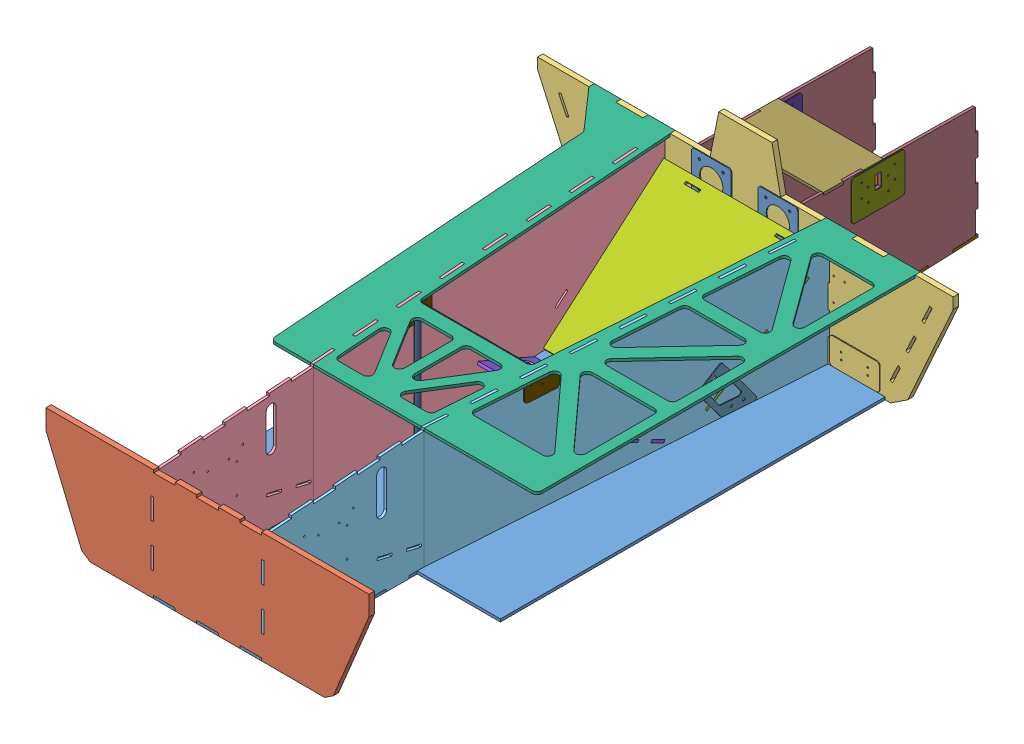
SolidWorks assembly Interior Frame, configuration Default. Lengths in mm.
Overall size (1586.02 634.29 2739.24).
38 component instances, 24 part files, 124 mates.
Components (placement in the parent):
- Floor Panel-1: Floor Panel [Default] at (835.5965 1316.5356 1074.9175) x (1 0 0) z (0 -1 0) size (1066.76 2072.64 10.16)
- Front Bulkhead-1: Front Bulkhead [Default] at (162.873 1776.2756 3127.2375) size (1232.36 425.45 20.32)
- Rearward Bulkhead-1: Rearward Bulkhead [Default] at (876.0943 1625.7899 1074.9175) size (1586.02 634.29 20.32)
- Part11-1: Part11 [Default] at (835.5965 1306.3756 1074.9175) x (1 0 0) z (0 -1 0) size (111.78 2072.64 469.9)
- MirrorPart11-2: MirrorPart11 [Default] at (835.5965 1306.3756 1074.9175) x (-1 0 0) z (0 1 0) size (111.78 2072.64 469.9)
- Part12-1: Part12 [Default] at (835.5965 1766.1156 1074.9175) x (-1 0 0) z (0 1 0) size (1244.67 1463.04 10.16)
- Part13-1: Part13 [Default] at origin
- Part14-1: Part14 [Default] at (835.5965 0 0) x (0 0 -1) z (1 0 0) size (499.77 372.73 622.87)
- Part15-1: Part15 [Default] at (835.5965 0 0) x (0 0 -1) z (1 0 0) size (234.38 107.63 550.98)
- Battery Tray-1: Battery Tray [Default] at (634.9365 1306.3843 1074.4968) x (1 0 0) z (0 -0.041404 0.999142) size (401.32 10.16 666.75)
- Part5^Interior Frame-1: Part5^Interior Frame [Default] at (0 0 2118.8575) size (473.12 449.58 19.05) (virtual)
- Part6^Interior Frame-1: Part6^Interior Frame [Default] at (0 0 2118.8575) size (50.8 31.75 1.65) (virtual)
- Part1^Interior Frame-1: Part1^Interior Frame [Default] at (1026.0965 1782.5715 1439.818) x (0 -0.013523 -0.999909) z (0 0.999909 -0.013523) size (228.6 401.32 10.16) (virtual)
- Shock Side Holder-1: Shock Side Holder [Default] at (634.9365 1306.3881 1094.817) x (0 0 -1) z (1 0 0) size (686.5 467.3 10.16)
- Shock Side Holder-2: Shock Side Holder [Default] at (1026.0965 1306.3881 1094.817) x (0 0 -1) z (1 0 0) size (686.5 467.3 10.16)
- Waist Seatbelt Bracket Outside-1: Waist Seatbelt Bracket Outside [Default] at (519.6209 1306.3756 1096.8642) x (0 -1 0) z (-0.997597 0 0.06929) size (178.19 207.85 3.17)
- Waist Seatbelt Bracket Outside-2: Waist Seatbelt Bracket Outside [Default] at (1154.7396 1306.3756 1097.0842) x (0 -1 0) z (-0.997597 0 -0.06929) size (178.19 207.85 3.17)
- Waist Seatbelt Bracket Inside-1: Waist Seatbelt Bracket Inside [Default] at (529.7386 1306.3756 1096.1614) x (0 1 0) z (0.997597 0 -0.06929) size (100.47 160.16 3.17)
- RearSuspensionBracketOutside-1: RearSuspensionBracketOutside [Default] at (634.9365 1306.3881 1094.817) x (0 0 1) z (-1 0 0) size (203.2 152.4 3.17)
- RearSuspensionBracketInside-1: RearSuspensionBracketInside [Default] at (645.0965 1306.3881 1094.817) x (0 0 -1) z (1 0 0) size (203.2 127 3.17)
- RearSuspensionBracketInside-2: RearSuspensionBracketInside [Default] at (1026.0965 1306.3881 488.5782) x (0 0 1) z (-1 0 0) size (203.2 127 3.17)
- RearSuspensionBracketOutside-2: RearSuspensionBracketOutside [Default] at (1039.4315 1306.3881 1094.817) x (0 0 1) z (-1 0 0) size (203.2 152.4 3.17)
- SteeringMountBracket-1: SteeringMountBracket [Default] at (519.6209 1306.3756 1096.8642) x (0 -1 0) z (-0.997597 0 0.06929) size (76.2 127 3.17)
- SteeringMountBracket-2: SteeringMountBracket [Default] at (671.7075 1306.3756 3140.1481) x (0 -1 0) z (0.997597 0 -0.06929) size (76.2 127 3.17)
- SteeringMountBracket-3: SteeringMountBracket [Default] at (1141.4545 1306.3756 1096.1614) x (0 -1 0) z (-0.997597 0 -0.06929) size (76.2 127 3.17)
- SteeringMountBracket-4: SteeringMountBracket [Default] at (1009.6032 1306.3756 3140.8508) x (0 -1 0) z (0.997597 0 0.06929) size (76.2 127 3.17)
- RollBarBackingPlate-1: RollBarBackingPlate [Default] at (876.0943 1625.7899 1095.2375) size (152.4 152.4 3.17)
- RollBarBackingPlate-2: RollBarBackingPlate [Default] at (795.0988 1625.7899 1098.4125) x (-1 0 0) z (0 0 -1) size (152.4 152.4 3.17)
- Array Support Backing Plate-1: Array Support Backing Plate [Default] at (876.0943 1625.7899 1095.2375) size (127 63.5 3.17)
- Rear Suspension Lower Backing Plate-1: Rear Suspension Lower Backing Plate [Default] at (876.0943 1625.7899 1095.2375) size (190.5 101.6 3.17)
- Rear Suspension Lower Backing Plate-2: Rear Suspension Lower Backing Plate [Default] at (37.6403 1625.7899 1095.2375) size (190.5 101.6 3.17)
- Part2^Interior Frame-1: Part2^Interior Frame [Default] at (876.0943 1625.7899 1074.9175) x (-1 0 0) z (0 0 -1) size (292.1 149.22 2.54) (virtual)
- Part2^Interior Frame-2: Part2^Interior Frame [Default] at (876.0943 1625.7899 1097.7775) x (-1 0 0) z (0 0 -1) size (292.1 149.22 2.54) (virtual)
- Part3^Interior Frame-1: Part3^Interior Frame [Default] at (835.5965 453.9768 -212.3723) x (0 -0.423732 -0.905788) z (0 0.905788 -0.423732) size (101.6 38.1 3.17) (virtual)
- Part3^Interior Frame-2: Part3^Interior Frame [Default] at (835.5965 441.8981 -206.7219) x (0 -0.423732 -0.905788) z (0 0.905788 -0.423732) size (101.6 38.1 3.17) (virtual)
- Part3^Interior Frame-3: Part3^Interior Frame [Default] at (1279.1452 453.9768 -212.3723) x (0 -0.423732 -0.905788) z (0 0.905788 -0.423732) size (101.6 38.1 3.17) (virtual)
- Part3^Interior Frame-4: Part3^Interior Frame [Default] at (1279.1452 441.8981 -206.7219) x (0 -0.423732 -0.905788) z (0 0.905788 -0.423732) size (101.6 38.1 3.17) (virtual)
- Waist Seatbelt Bracket Inside-2: Waist Seatbelt Bracket Inside [Default] at (1138.2871 1306.3756 1095.9414) x (0 1 0) z (0.997597 0 0.06929) size (100.47 160.16 3.17)
Mates (geometry in assembly coordinates):
- Coincident5: coincident: point of Floor Panel-1; plane of Rearward Bulkhead-1 through (835.5965 1625.7899 1074.9175) normal (1 0 0)
- Coincident6: coincident aligned: plane of Floor Panel-1 through (835.5965 1306.3756 1074.9175) normal (0 -1 0); plane of Rearward Bulkhead-1 through (876.0943 1306.3756 1095.2375) normal (0 -1 0)
- Coincident7: coincident aligned: plane of Floor Panel-1 through (835.5965 1306.3756 1074.9175) normal (0 0 -1); plane of Rearward Bulkhead-1 through (876.0943 1625.7899 1074.9175) normal (0 0 -1)
- InPlace1: in place: plane of Floor Panel-1 through (835.5965 1306.3756 1074.9175) normal (0 -1 0); plane of ? through (0 1306.3756 0) normal (0 -1 0); moOrthogonalPlaneRef_w of Floor Panel-1 through (835.5965 1306.3756 1074.9175) normal (0 -1 0); plane of ? through (0 1306.3756 0) normal (0 0 -1); plane of Floor Panel-1 through (835.5965 1306.3756 1074.9175) normal (0 -1 0); plane of ? through (0 1306.3756 0) normal (-1 0 0); plane of Floor Panel-1 through (835.5965 1306.3756 1074.9175) normal (0 -1 0); unknown of Part11-1
- Coincident8: coincident aligned: plane of Floor Panel-1; plane of Part11-1
- Coincident9: coincident aligned: moOrthogonalPlaneRef_w of Floor Panel-1 through (835.5965 1306.3756 1074.9175) normal (0 0 1); plane of Part11-1 through (835.5965 1306.3756 1074.9175) normal (0 0 1)
- Coincident10: coincident anti-aligned: moOrthogonalPlaneRef_w of Floor Panel-1 through (835.5965 1306.3756 1074.9175) normal (-1 0 0); plane of Part11-1 through (835.5965 1306.3756 1074.9175) normal (1 0 0)
- InPlace2: in place: plane of Part11-1 through (554.4334 1766.1156 1089.5649) normal (0 1 0); plane of ? through (0 1766.1156 0) normal (0 1 0); plane of Part11-1 through (554.4334 1766.1156 1089.5649) normal (0 1 0); plane of ? through (0 1766.1156 0) normal (0 0 -1); plane of Part11-1 through (554.4334 1766.1156 1089.5649) normal (0 1 0); plane of ? through (0 1766.1156 0) normal (1 0 0); plane of Part11-1 through (529.7565 1766.1156 1096.1602) normal (0 1 0); unknown of Part12-1
- Coincident11: coincident aligned: plane of Part11-1; plane of Part12-1
- Coincident12: coincident aligned: moOrthogonalPlaneRef_w of Part11-1 through (835.5965 1766.1156 1074.9175) normal (0 0 1); plane of Part12-1 through (835.5965 1766.1156 1074.9175) normal (0 0 1)
- Coincident13: coincident anti-aligned: moOrthogonalPlaneRef_w of Part11-1 through (835.5965 1766.1156 1074.9175) normal (1 0 0); plane of Part12-1 through (835.5965 1766.1156 1074.9175) normal (-1 0 0)
- InPlace3: in place: plane of ? through (835.5965 0 0) normal (1 0 0); plane of ? through (835.5965 0 0) normal (0 1 0); plane of ? through (835.5965 0 0) normal (0 0 -1); unknown of ?
- Coincident14: coincident aligned: 
- Coincident15: coincident aligned: plane of Part14-1 through (835.5965 0 0) normal (0 1 0)
- Coincident16: coincident anti-aligned: plane of Part14-1 through (835.5965 0 0) normal (0 0 -1)
- InPlace4: in place: plane of ? through (835.5965 0 0) normal (1 0 0); plane of ? through (835.5965 0 0) normal (0 1 0); plane of ? through (835.5965 0 0) normal (0 0 -1); unknown of ?
- Coincident17: coincident aligned: 
- Coincident18: coincident aligned: plane of Part15-1 through (835.5965 0 0) normal (0 1 0)
- Coincident19: coincident anti-aligned: plane of Part15-1 through (835.5965 0 0) normal (0 0 -1)
- InPlace6: in place: plane of ? through (0 0 2118.8575) normal (0 0 1); plane of ? through (0 0 2118.8575) normal (0 1 0); plane of ? through (0 0 2118.8575) normal (1 0 0); unknown of ?
- Coincident32: coincident aligned: 
- Coincident33: coincident aligned: plane of Part5^Interior Frame-1 through (0 0 2118.8575) normal (0 1 0)
- Coincident34: coincident anti-aligned: plane of Part5^Interior Frame-1 through (0 0 2118.8575) normal (1 0 0)
- InPlace7: in place: plane of ? through (0 0 2118.8575) normal (0 0 1); plane of ? through (0 0 2118.8575) normal (0 1 0); plane of ? through (0 0 2118.8575) normal (1 0 0); unknown of ?
- Coincident35: coincident aligned: 
- Coincident36: coincident aligned: plane of Part6^Interior Frame-1 through (0 0 2118.8575) normal (0 1 0)
- Coincident37: coincident anti-aligned: plane of Part6^Interior Frame-1 through (0 0 2118.8575) normal (1 0 0)
- Coincident24: coincident anti-aligned: line of Floor Panel-1 through (1116.5713 1316.5356 1074.9175) axis (-1 0 0); line of Battery Tray-1 through (634.9365 1316.5356 1074.9175) axis (1 0 0)
- Coincident25: coincident anti-aligned: plane of Battery Side Holder-2 through (1036.2565 1315.6776 1095.6232) normal (0 -0.999142 -0.041404); plane of Battery Tray-1 through (634.9365 1316.5356 1074.9175) normal (0 0.999142 0.041404)
- Coincident29: coincident anti-aligned: plane of Battery Side Holder-1 through (645.0965 1306.3669 1095.2375) normal (1 0 0); plane of Battery Tray-1 through (645.0965 1316.5356 1074.9175) normal (-1 0 0)
- Coincident30: coincident aligned: plane of Battery Side Holder-1 through (645.0965 1305.5263 1095.2027) normal (0 -0.999142 -0.041404); plane of Battery Tray-1 through (634.9365 1306.3843 1074.4968) normal (0 -0.999142 -0.041404)
- Coincident31: coincident anti-aligned: plane of Rearward Bulkhead-1 through (876.0943 1625.7899 1074.9175) normal (0 0 -1); plane of Battery Side Holder-1 through (645.0965 1306.3669 1074.9175) normal (0 0 1)
- Coincident32: coincident anti-aligned: plane of Rearward Bulkhead-1 through (876.0943 1625.7899 1074.9175) normal (0 0 -1); plane of Battery Side Holder-2 through (1036.2565 1306.3707 1074.9175) normal (0 0 1)
- Coincident33: coincident anti-aligned: plane of Battery Side Holder-2 through (1026.0965 1306.3707 1095.2375) normal (-1 0 0); plane of Battery Tray-1 through (1026.0965 1316.5356 1074.9175) normal (1 0 0)
- Coincident34: coincident: unknown of Battery Tray-1
- Coincident35: coincident anti-aligned: plane of Battery Side Holder-1 through (645.0965 1306.3669 1095.2375) normal (1 0 0); plane of Part1^Interior Frame-1 through (645.0965 1772.4125 1439.9553) normal (-1 0 0)
- Distance1: distance = 10.16 mm aligned: plane of Battery Side Holder-1 through (645.0965 1767.6354 1088.9993) normal (0 0.999909 -0.013523); plane of Part1^Interior Frame-1 through (1026.0965 1782.5715 1439.818) normal (0 0.999909 -0.013523)
- Coincident36: coincident anti-aligned: plane of Battery Tray-1 through (634.9365 1316.5356 1074.9175) normal (0 0.999142 0.041404); plane of Shock Side Holder-1 through (645.0965 1315.695 1095.2027) normal (0 -0.999142 -0.041404)
- Coincident37: coincident anti-aligned: plane of Battery Tray-1 through (634.9365 1340.1979 503.9076) normal (0 -0.041404 0.999142); plane of Shock Side Holder-1 through (645.0965 1330.891 503.5219) normal (0 0.041404 -0.999142)
- Coincident38: coincident anti-aligned: plane of Battery Tray-1 through (645.0965 1316.5356 1074.9175) normal (-1 0 0); plane of Shock Side Holder-1 through (645.0965 1306.3881 1094.817) normal (1 0 0)
- Parallel1: parallel anti-aligned: plane of Rearward Bulkhead-1 through (876.0943 1625.7899 1074.9175) normal (0 0 -1); plane of Shock Side Holder-1 through (645.0965 1306.3881 1074.497) normal (0 0 1)
- Coincident40: coincident anti-aligned: plane of Part1^Interior Frame-1 through (1026.0965 1772.4125 1439.9553) normal (0 -0.999909 0.013523); plane of Shock Side Holder-1 through (645.0965 1767.6605 1088.5788) normal (0 0.999909 -0.013523)
- Coincident41: coincident aligned: plane of Part1^Interior Frame-1 through (634.9365 1772.4125 1439.9553) normal (-1 0 0); plane of Shock Side Holder-1 through (634.9365 1306.3881 1094.817) normal (-1 0 0)
- Coincident46: coincident: line of Part1^Interior Frame-1 through (1036.2565 1776.6005 998.297) axis (-1 0 0); plane of Shock Side Holder-1 through (645.0965 1776.5967 998.297) normal (0 0 -1)
- Coincident47: coincident anti-aligned: plane of Battery Tray-1 through (634.9365 1316.5356 1074.9175) normal (0 0.999142 0.041404); plane of Shock Side Holder-2 through (1036.2565 1315.695 1095.2027) normal (0 -0.999142 -0.041404)
- Coincident48: coincident aligned: plane of Battery Tray-1 through (1036.2565 1316.5356 1074.9175) normal (1 0 0); plane of Shock Side Holder-2 through (1036.2565 1306.3881 1094.817) normal (1 0 0)
- Coincident49: coincident anti-aligned: plane of Battery Tray-1 through (634.9365 1340.1979 503.9076) normal (0 -0.041404 0.999142); plane of Shock Side Holder-2 through (1036.2565 1330.891 503.5219) normal (0 0.041404 -0.999142)
- Concentric1: concentric aligned: cylinder of Part11-1 through (679.4011 1342.3102 1787.8763) axis (-0.997597 0 0.06929) radius 4.7625; cylinder of Bottom Seatbelt Holder-1 through (568.1531 1342.3102 1795.6032) axis (-0.997597 0 0.06929) radius 4.7625
- Coincident50: coincident anti-aligned: plane of Part11-1 through (519.5079 1776.2756 1095.2375) normal (-0.997597 0 0.06929); plane of Bottom Seatbelt Holder-1 through (523.5309 1064.5391 1153.1587) normal (0.997597 0 -0.06929)
- Concentric2: concentric aligned: cylinder of Part11-1 through (676.8892 1333.851 1751.7104) axis (-0.997597 0 0.06929) radius 4.7625; cylinder of Bottom Seatbelt Holder-1 through (565.6412 1333.851 1759.4374) axis (-0.997597 0 0.06929) radius 4.7625
- Concentric3: concentric anti-aligned: cylinder of Part11-1 through (654.9325 1341.9356 1435.5902) axis (-0.997597 0 0.06929) radius 4.7625; cylinder of Waist Seatbelt Bracket Outside-1 through (540.5171 1341.9356 1443.5371) axis (0.997597 0 -0.06929) radius 4.7625
- Coincident52: coincident anti-aligned: plane of Part11-1 through (519.5079 1776.2756 1095.2375) normal (-0.997597 0 0.06929); plane of Waist Seatbelt Bracket Outside-1 through (519.6209 1306.3756 1096.8642) normal (0.997597 0 -0.06929)
- Concentric4: concentric anti-aligned: cylinder of Part11-1 through (651.8525 1341.9356 1391.247) axis (-0.997597 0 0.06929) radius 4.7625; cylinder of Waist Seatbelt Bracket Outside-1 through (537.4371 1341.9356 1399.194) axis (0.997597 0 -0.06929) radius 4.7625
- Lock1: lock: unknown of Bottom Seatbelt Holder-1; unknown of Bottom Seatbelt Holder-4
- Concentric5: concentric aligned: cylinder of Part11-1 through (679.4011 1342.3102 1787.8763) axis (-0.997597 0 0.06929) radius 4.7625; cylinder of Bottom Seatbelt Holder-4 through (581.4382 1342.3102 1794.6805) axis (-0.997597 0 0.06929) radius 4.7625
- Concentric6: concentric aligned: cylinder of Part11-1 through (676.8892 1333.851 1751.7104) axis (-0.997597 0 0.06929) radius 4.7625; cylinder of Bottom Seatbelt Holder-4 through (578.9262 1333.851 1758.5146) axis (-0.997597 0 0.06929) radius 4.7625
- Coincident53: coincident anti-aligned: plane of Part11-1 through (629.8812 1776.2756 2537.9575) normal (0.997597 0 -0.06929); plane of Bottom Seatbelt Holder-4 through (533.6486 1064.5391 1152.4559) normal (-0.997597 0 0.06929)
- Concentric7: concentric aligned: cylinder of MirrorPart11-2 through (991.7919 1342.3102 1787.8763) axis (0.997597 0 0.06929) radius 4.7625; cylinder of Bottom Seatbelt Holder-2 through (1089.7549 1342.3102 1794.6805) axis (0.997597 0 0.06929) radius 4.7625
- Coincident54: coincident anti-aligned: plane of MirrorPart11-2 through (1041.3118 1776.2756 2537.9575) normal (-0.997597 0 -0.06929); plane of Bottom Seatbelt Holder-2 through (1141.4545 1306.3756 1096.1614) normal (0.997597 0 0.06929)
- Concentric8: concentric aligned: cylinder of MirrorPart11-2 through (994.3039 1333.851 1751.7104) axis (0.997597 0 0.06929) radius 4.7625; cylinder of Bottom Seatbelt Holder-2 through (1092.2669 1333.851 1758.5146) axis (0.997597 0 0.06929) radius 4.7625
- Concentric12: concentric anti-aligned: cylinder of MirrorPart11-2 through (991.7919 1342.3102 1787.8763) axis (0.997597 0 0.06929) radius 4.7625; cylinder of Bottom Seatbelt Holder-3 through (1106.2073 1342.3102 1795.8232) axis (-0.997597 0 -0.06929) radius 4.7625
- Coincident56: coincident aligned: cylinder of MirrorPart11-2 through (994.3039 1333.851 1751.7104) axis (0.997597 0 0.06929) radius 4.7625; circle of Bottom Seatbelt Holder-3
- Coincident57: coincident anti-aligned: plane of MirrorPart11-2 through (1151.6852 1776.2756 1095.2375) normal (0.997597 0 0.06929); plane of Bottom Seatbelt Holder-3 through (1147.6622 1064.5391 1153.1587) normal (-0.997597 0 -0.06929)
- Concentric13: concentric aligned: cylinder of MirrorPart11-2 through (1016.2606 1341.9356 1435.5902) axis (0.997597 0 0.06929) radius 4.7625; cylinder of Waist Seatbelt Bracket Outside-2 through (1127.5087 1341.9356 1443.3171) axis (0.997597 0 0.06929) radius 4.7625
- Coincident58: coincident anti-aligned: plane of MirrorPart11-2 through (1151.6852 1776.2756 1095.2375) normal (0.997597 0 0.06929); plane of Waist Seatbelt Bracket Outside-2 through (1151.5722 1306.3756 1096.8642) normal (-0.997597 0 -0.06929)
- Concentric14: concentric aligned: cylinder of MirrorPart11-2 through (1019.3406 1341.9356 1391.247) axis (0.997597 0 0.06929) radius 4.7625; cylinder of Waist Seatbelt Bracket Outside-2 through (1130.5886 1341.9356 1398.974) axis (0.997597 0 0.06929) radius 4.7625
- InPlace8: in place: plane of Part11-1 through (629.8812 1776.2756 2537.9575) normal (0.997597 0 -0.06929); plane of ? through (451.4248 0 -31.3546) normal (0.997597 0 -0.06929); plane of Part11-1 through (629.8812 1776.2756 2537.9575) normal (0.997597 0 -0.06929); plane of ? through (451.4248 0 -31.3546) normal (0 1 0); plane of Part11-1 through (629.8812 1776.2756 2537.9575) normal (0.997597 0 -0.06929); plane of ? through (451.4248 0 -31.3546) normal (-0.06929 0 -0.997597); plane of Part11-1 through (629.8812 1776.2756 2537.9575) normal (0.997597 0 -0.06929); unknown of Waist Seatbelt Bracket Inside-1
- Coincident59: coincident aligned: plane of Part11-1; plane of Waist Seatbelt Bracket Inside-1
- Coincident60: coincident aligned: moOrthogonalPlaneRef_w of Part11-1 through (529.7386 1306.3756 1096.1614) normal (0.06929 0 0.997597); plane of Waist Seatbelt Bracket Inside-1 through (529.7386 1306.3756 1096.1614) normal (0.06929 0 0.997597)
- Coincident61: coincident anti-aligned: moOrthogonalPlaneRef_w of Part11-1 through (529.7386 1306.3756 1096.1614) normal (0 -1 0); plane of Waist Seatbelt Bracket Inside-1 through (529.7386 1306.3756 1096.1614) normal (0 1 0)
- InPlace9: in place: plane of Shock Side Holder-1 through (634.9365 1306.3881 1094.817) normal (-1 0 0); plane of ? through (634.9365 0 0) normal (-1 0 0); plane of Shock Side Holder-1 through (634.9365 1306.3881 1094.817) normal (-1 0 0); plane of ? through (634.9365 0 0) normal (0 1 0); plane of Shock Side Holder-1 through (634.9365 1306.3881 1094.817) normal (-1 0 0); plane of ? through (634.9365 0 0) normal (0 0 1); plane of Shock Side Holder-1 through (634.9365 1306.3881 1094.817) normal (-1 0 0); unknown of RearSuspensionBracketOutside-1
- Coincident59: coincident aligned: plane of Shock Side Holder-1; plane of RearSuspensionBracketOutside-1
- Coincident60: coincident aligned: moOrthogonalPlaneRef_w of Shock Side Holder-1 through (634.9365 1306.3881 1094.817) normal (0 1 0); plane of Part2^Interior Frame-1 through (634.9365 1306.3881 1094.817) normal (0 1 0)
- Coincident61: coincident anti-aligned: moOrthogonalPlaneRef_w of Shock Side Holder-1 through (634.9365 1306.3881 1094.817) normal (0 0 -1); plane of Part2^Interior Frame-1 through (634.9365 1306.3881 1094.817) normal (0 0 1)
- InPlace10: in place: plane of Shock Side Holder-1 through (645.0965 1306.3881 1094.817) normal (1 0 0); plane of ? through (645.0965 0 0) normal (1 0 0); plane of Shock Side Holder-1 through (645.0965 1306.3881 1094.817) normal (1 0 0); plane of ? through (645.0965 0 0) normal (0 1 0); plane of Shock Side Holder-1 through (645.0965 1306.3881 1094.817) normal (1 0 0); plane of ? through (645.0965 0 0) normal (0 0 -1); plane of Shock Side Holder-1 through (645.0965 1306.3881 1094.817) normal (1 0 0); unknown of RearSuspensionBracketInside-1
- Coincident59: coincident aligned: plane of Shock Side Holder-1; plane of RearSuspensionBracketInside-1
- Coincident60: coincident aligned: moOrthogonalPlaneRef_w of Shock Side Holder-1 through (645.0965 1306.3881 1094.817) normal (0 1 0); plane of Part3^Interior Frame-1 through (645.0965 1306.3881 1094.817) normal (0 1 0)
- Coincident61: coincident anti-aligned: moOrthogonalPlaneRef_w of Shock Side Holder-1 through (645.0965 1306.3881 1094.817) normal (0 0 1); plane of Part3^Interior Frame-1 through (645.0965 1306.3881 1094.817) normal (0 0 -1)
- Coincident62: coincident anti-aligned: line of Shock Side Holder-2 through (1026.0965 1687.359 804.3976) axis (0 0 -1); line of RearSuspensionBracketInside-2 through (1026.0965 1687.359 778.9976) axis (0 0 1)
- Concentric15: concentric aligned: cylinder of Shock Side Holder-2 through (1026.0965 1661.959 753.5976) axis (1 0 0) radius 3.175; cylinder of RearSuspensionBracketInside-2 through (1022.9215 1661.959 753.5976) axis (1 0 0) radius 3.175
- Coincident64: coincident aligned: line of Shock Side Holder-2 through (1036.2565 1687.359 804.3976) axis (0 0 -1); line of RearSuspensionBracketOutside-2 through (1036.2565 1687.359 804.3976) axis (0 0 -1)
- Concentric16: concentric aligned: cylinder of Shock Side Holder-2 through (1026.0965 1661.959 753.5976) axis (1 0 0) radius 3.175; cylinder of RearSuspensionBracketOutside-2 through (1036.2565 1661.959 753.5976) axis (1 0 0) radius 3.175
- InPlace11: in place: plane of Part11-1 through (519.5079 1776.2756 1095.2375) normal (-0.997597 0 0.06929); plane of ? through (441.3071 0 -30.6518) normal (-0.997597 0 0.06929); plane of Part11-1 through (519.5079 1776.2756 1095.2375) normal (-0.997597 0 0.06929); plane of ? through (441.3071 0 -30.6518) normal (0 1 0); plane of Part11-1 through (519.5079 1776.2756 1095.2375) normal (-0.997597 0 0.06929); plane of ? through (441.3071 0 -30.6518) normal (0.06929 0 0.997597); plane of Part11-1 through (519.5079 1776.2756 1095.2375) normal (-0.997597 0 0.06929); unknown of ?
- Coincident65: coincident aligned: plane of Part11-1; plane of SteeringMountBracket-1
- Coincident66: coincident aligned: moOrthogonalPlaneRef_w of Part11-1 through (519.6209 1306.3756 1096.8642) normal (0.06929 0 0.997597); plane of SteeringMountBracket-1 through (519.6209 1306.3756 1096.8642) normal (0.06929 0 0.997597)
- Coincident67: coincident anti-aligned: moOrthogonalPlaneRef_w of Part11-1 through (519.6209 1306.3756 1096.8642) normal (0 1 0); plane of SteeringMountBracket-1 through (519.6209 1306.3756 1096.8642) normal (0 -1 0)
- Coincident68: coincident aligned: circle of Part11-1; circle of SteeringMountBracket-2
- Concentric17: concentric aligned: cylinder of Part11-1 through (704.4933 1743.8906 2149.139) axis (-0.997597 0 0.06929) radius 3.175; cylinder of SteeringMountBracket-2 through (606.5304 1743.8906 2155.9432) axis (-0.997597 0 0.06929) radius 3.175
- Concentric18: concentric aligned: cylinder of MirrorPart11-2 through (966.6998 1743.8906 2149.139) axis (0.997597 0 0.06929) radius 3.175; cylinder of SteeringMountBracket-3 through (1064.6627 1743.8906 2155.9432) axis (0.997597 0 0.06929) radius 3.175
- Coincident69: coincident anti-aligned: circle of MirrorPart11-2; circle of SteeringMountBracket-3
- Coincident70: coincident anti-aligned: circle of MirrorPart11-2; circle of SteeringMountBracket-4
- Concentric19: concentric anti-aligned: cylinder of MirrorPart11-2 through (971.9797 1743.8906 2073.1221) axis (0.997597 0 0.06929) radius 3.175; cylinder of SteeringMountBracket-4 through (1086.395 1743.8906 2081.0691) axis (-0.997597 0 -0.06929) radius 3.175
- InPlace12: in place: plane of Rearward Bulkhead-1 through (876.0943 1625.7899 1095.2375) normal (0 0 1); plane of ? through (0 0 1095.2375) normal (0 0 1); plane of Rearward Bulkhead-1 through (876.0943 1625.7899 1095.2375) normal (0 0 1); plane of ? through (0 0 1095.2375) normal (0 1 0); plane of Rearward Bulkhead-1 through (876.0943 1625.7899 1095.2375) normal (0 0 1); plane of ? through (0 0 1095.2375) normal (1 0 0); plane of Rearward Bulkhead-1 through (876.0943 1625.7899 1095.2375) normal (0 0 1); unknown of ?
- Coincident71: coincident aligned: plane of Rearward Bulkhead-1; plane of RollBarBackingPlate-1
- Coincident72: coincident aligned: moOrthogonalPlaneRef_w of Rearward Bulkhead-1 through (876.0943 1625.7899 1095.2375) normal (0 1 0); plane of RollBarBackingPlate-1 through (876.0943 1625.7899 1095.2375) normal (0 1 0)
- Coincident73: coincident anti-aligned: moOrthogonalPlaneRef_w of Rearward Bulkhead-1 through (876.0943 1625.7899 1095.2375) normal (-1 0 0); plane of RollBarBackingPlate-1 through (876.0943 1625.7899 1095.2375) normal (1 0 0)
- Coincident74: coincident anti-aligned: plane of Rearward Bulkhead-1 through (876.0943 1625.7899 1095.2375) normal (0 0 1); plane of RollBarBackingPlate-2 through (795.0988 1625.7899 1095.2375) normal (0 0 -1)
- Concentric20: concentric anti-aligned: cylinder of Rearward Bulkhead-1 through (1007.872 1750.8756 1095.6221) axis (0 0 -1) radius 4.7625; cylinder of RollBarBackingPlate-2 through (1007.872 1750.8756 1095.2375) axis (0 0 1) radius 4.7625
- InPlace13: in place: plane of Rearward Bulkhead-1 through (876.0943 1625.7899 1095.2375) normal (0 0 1); plane of ? through (0 0 1095.2375) normal (0 0 1); plane of Rearward Bulkhead-1 through (876.0943 1625.7899 1095.2375) normal (0 0 1); plane of ? through (0 0 1095.2375) normal (0 1 0); plane of Rearward Bulkhead-1 through (876.0943 1625.7899 1095.2375) normal (0 0 1); plane of ? through (0 0 1095.2375) normal (1 0 0); plane of Rearward Bulkhead-1 through (876.0943 1625.7899 1095.2375) normal (0 0 1); unknown of ?
- Coincident76: coincident aligned: plane of Rearward Bulkhead-1; plane of Array Support Backing Plate-1
- Coincident77: coincident aligned: moOrthogonalPlaneRef_w of Rearward Bulkhead-1 through (876.0943 1625.7899 1095.2375) normal (0 1 0); plane of Array Support Backing Plate-1 through (876.0943 1625.7899 1095.2375) normal (0 1 0)
- Coincident78: coincident anti-aligned: moOrthogonalPlaneRef_w of Rearward Bulkhead-1 through (876.0943 1625.7899 1095.2375) normal (-1 0 0); plane of Array Support Backing Plate-1 through (876.0943 1625.7899 1095.2375) normal (1 0 0)
- InPlace14: in place: plane of Rearward Bulkhead-1 through (876.0943 1625.7899 1095.2375) normal (0 0 1); plane of ? through (0 0 1095.2375) normal (0 0 1); plane of Rearward Bulkhead-1 through (876.0943 1625.7899 1095.2375) normal (0 0 1); plane of ? through (0 0 1095.2375) normal (0 1 0); plane of Rearward Bulkhead-1 through (876.0943 1625.7899 1095.2375) normal (0 0 1); plane of ? through (0 0 1095.2375) normal (1 0 0); plane of Rearward Bulkhead-1 through (876.0943 1625.7899 1095.2375) normal (0 0 1); unknown of ?
- Coincident79: coincident aligned: plane of Rearward Bulkhead-1; plane of Rear Suspension Lower Backing Plate-1
- Coincident80: coincident aligned: moOrthogonalPlaneRef_w of Rearward Bulkhead-1 through (876.0943 1625.7899 1095.2375) normal (0 1 0); plane of Rear Suspension Lower Backing Plate-1 through (876.0943 1625.7899 1095.2375) normal (0 1 0)
- Coincident81: coincident anti-aligned: moOrthogonalPlaneRef_w of Rearward Bulkhead-1 through (876.0943 1625.7899 1095.2375) normal (-1 0 0); plane of Rear Suspension Lower Backing Plate-1 through (876.0943 1625.7899 1095.2375) normal (1 0 0)
- Coincident83: coincident anti-aligned: plane of Rearward Bulkhead-1 through (876.0943 1625.7899 1095.2375) normal (0 0 1); plane of Rear Suspension Lower Backing Plate-2 through (37.6403 1625.7899 1095.2375) normal (0 0 -1)
- Concentric21: concentric aligned: cylinder of Rearward Bulkhead-1 through (467.1695 1357.5312 1104.2177) axis (0 0 -1) radius 3.175; cylinder of Rear Suspension Lower Backing Plate-2 through (467.1695 1357.5312 1098.4125) axis (0 0 -1) radius 3.175
- Concentric22: concentric aligned: cylinder of Rearward Bulkhead-1 through (365.5695 1382.9312 1104.2177) axis (0 0 -1) radius 3.175; cylinder of Rear Suspension Lower Backing Plate-2 through (365.5695 1382.9312 1098.4125) axis (0 0 -1) radius 3.175
- InPlace15: in place: plane of Rearward Bulkhead-1 through (876.0943 1625.7899 1074.9175) normal (0 0 -1); plane of ? through (0 0 1074.9175) normal (0 0 -1); plane of Rearward Bulkhead-1 through (876.0943 1625.7899 1074.9175) normal (0 0 -1); plane of ? through (0 0 1074.9175) normal (0 1 0); plane of Rearward Bulkhead-1 through (876.0943 1625.7899 1074.9175) normal (0 0 -1); plane of ? through (0 0 1074.9175) normal (-1 0 0); plane of Rearward Bulkhead-1 through (876.0943 1625.7899 1074.9175) normal (0 0 -1); unknown of Part2^Interior Frame-1
- Coincident84: coincident aligned: plane of Rearward Bulkhead-1; plane of Part2^Interior Frame-1
- Coincident85: coincident aligned: moOrthogonalPlaneRef_w of Rearward Bulkhead-1 through (876.0943 1625.7899 1074.9175) normal (0 1 0); plane of Part2^Interior Frame-1 through (876.0943 1625.7899 1074.9175) normal (0 1 0)
- Coincident86: coincident anti-aligned: moOrthogonalPlaneRef_w of Rearward Bulkhead-1 through (876.0943 1625.7899 1074.9175) normal (1 0 0); plane of Part2^Interior Frame-1 through (876.0943 1625.7899 1074.9175) normal (-1 0 0)
- Coincident89: coincident anti-aligned: circle of Rearward Bulkhead-1; circle of Part2^Interior Frame-2
- InPlace16: in place: plane of ? through (1364.5171 1424.1634 1861.5429) normal (0 0.905788 -0.423732); plane of ? through (0 453.9768 -212.3723) normal (0 0.905788 -0.423732); plane of ? through (1364.5171 1424.1634 1861.5429) normal (0 0.905788 -0.423732); plane of ? through (0 453.9768 -212.3723) normal (0 -0.423732 -0.905788); plane of ? through (1364.5171 1424.1634 1861.5429) normal (0 0.905788 -0.423732); plane of ? through (0 453.9768 -212.3723) normal (1 0 0); plane of ? through (1364.5171 1424.1634 1861.5429) normal (0 0.905788 -0.423732); unknown of Part3^Interior Frame-1
- Coincident90: coincident aligned: plane of Part15-1; plane of Part3^Interior Frame-1
- Coincident91: coincident aligned: moOrthogonalPlaneRef_w of Part15-1 through (835.5965 453.9768 -212.3723) normal (-1 0 0); plane of Part3^Interior Frame-1 through (835.5965 453.9768 -212.3723) normal (-1 0 0)
- Coincident92: coincident anti-aligned: moOrthogonalPlaneRef_w of Part15-1 through (835.5965 453.9768 -212.3723) normal (0 0.423732 0.905788); plane of Part3^Interior Frame-1 through (835.5965 453.9768 -212.3723) normal (0 -0.423732 -0.905788)
- Coincident93: coincident aligned: circle of Part15-1; circle of Part3^Interior Frame-2
- Concentric23: concentric anti-aligned: cylinder of Part15-1 through (613.8222 1258.8682 1742.5755) axis (0 0.905788 -0.423732) radius 4.7625; cylinder of Part3^Interior Frame-2 through (613.8222 1339.6211 1704.7989) axis (0 -0.905788 0.423732) radius 4.7625
- Coincident94: coincident aligned: circle of Part15-1; circle of Part3^Interior Frame-3
- Concentric24: concentric anti-aligned: cylinder of Part15-1 through (1057.3709 1258.8682 1742.5755) axis (0 0.905788 -0.423732) radius 4.7625; cylinder of Part3^Interior Frame-3 through (1057.3709 1351.6998 1699.1485) axis (0 -0.905788 0.423732) radius 4.7625
- Coincident95: coincident aligned: circle of Part15-1; circle of Part3^Interior Frame-4
- Concentric25: concentric anti-aligned: cylinder of Part15-1 through (1057.3709 1258.8682 1742.5755) axis (0 0.905788 -0.423732) radius 4.7625; cylinder of Part3^Interior Frame-4 through (1057.3709 1339.6211 1704.7989) axis (0 -0.905788 0.423732) radius 4.7625
